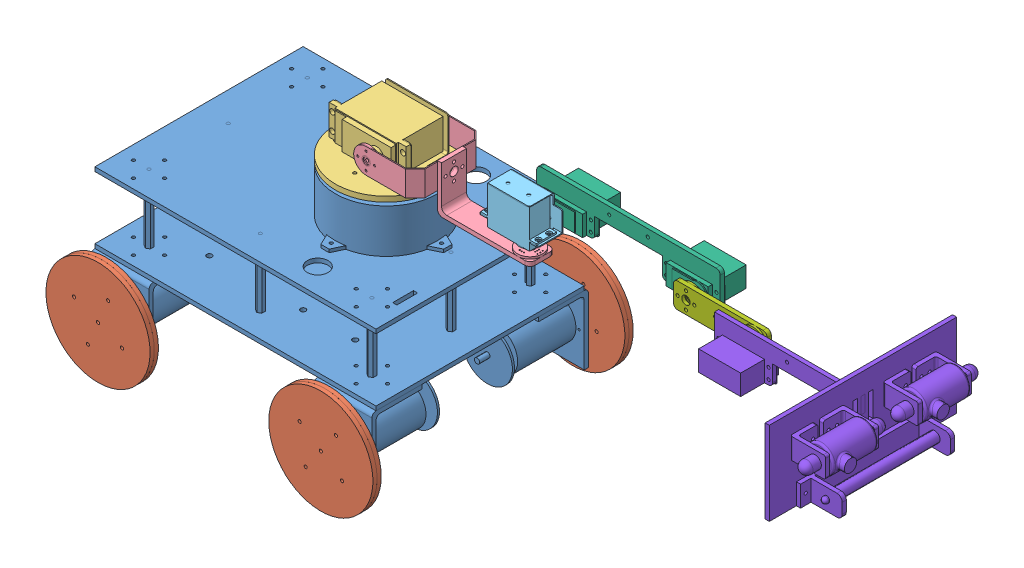
SolidWorks assembly exa_robot16, configuration Default. Lengths in mm.
Overall size (729.39 347.05 342.18).
11 component instances, 8 part files, 26 mates.
Components (placement in the parent):
- base_robot-1: base_robot [Default] at (14.2374 -23.114 -6.4589) size (270 179.13 234)
- roda_robot_fix-1: roda_robot_fix [Default] at (268.1239 -5.9891 251.6556) x (0.408711 0.912664 0) z (0 0 1) size (100 100 21)
- roda_robot_fix-2: roda_robot_fix [Default] at (-24.7206 118.9318 251.6556) x (-0.199609 -0.979876 0) z (0 0 1) size (100 100 21)
- roda_robot_fix-3: roda_robot_fix [Default] at (-43.3679 96.894 162.7099) x (0.933321 0.359042 0) z (0 0 -1) size (100 100 21)
- roda_robot_fix-4: roda_robot_fix [Default] at (229.5868 134.8934 162.7099) x (0.816348 -0.57756 0) z (0 0 -1) size (100 100 21)
- link1_robot-1: link1_robot [Default] at (14.2374 -23.114 -6.4589) size (98 43 98)
- link2_robot-1: link2_robot [Default] at (157.8184 543.2778 -6.4589) x (-0.766044 -0.642788 0) z (0 0 1) size (99.47 123.93 66)
- link3_robot-1: link3_robot [Default] at (157.8184 543.2778 -6.4589) x (-0.766044 -0.642788 0) z (0 0 1) size (56.44 54.96 29)
- link4_robot-1: link4_robot [Default] at (-3.6112 75.6154 -6.4589) x (0.642788 -0.766044 0) z (0 0 1) size (137.73 155 42.35)
- link5_robot-1: link5_robot [Default] at (605.5051 -228.2842 -6.4589) x (0.766044 0.642788 0) z (0 0 1) size (81.1 72.97 14)
- link6_eof_robot-1: link6_eof_robot [Default] at (291.8049 -177.1524 -6.4589) size (184.63 80 180)
Mates (geometry in assembly coordinates):
- Coincident1: coincident anti-aligned: plane of base_robot-1 through (258.5015 16.6149 311.1827) normal (0 0 1); plane of roda_robot_fix-1 through (235.6028 60.827 311.1827) normal (0 0 -1)
- Concentric1: concentric aligned: cylinder of base_robot-1 through (235.6028 60.827 324.1827) axis (0 0 -1) radius 2.5; cylinder of roda_robot_fix-1 through (235.6028 60.827 324.1827) axis (0 0 -1) radius 2.5
- Concentric2: concentric aligned: cylinder of base_robot-1 through (235.6028 60.827 90.1827) axis (0 0 1) radius 2.5; cylinder of roda_robot_fix-4 through (235.6028 60.827 90.1827) axis (0 0 1) radius 2.5
- Coincident3: coincident anti-aligned: plane of base_robot-1 through (212.704 16.6149 103.1827) normal (0 0 -1); plane of roda_robot_fix-4 through (235.6028 60.827 103.1827) normal (0 0 1)
- Coincident4: coincident anti-aligned: plane of base_robot-1 through (-1.296 105.0391 311.1827) normal (0 0 1); plane of roda_robot_fix-2 through (21.6028 60.827 311.1827) normal (0 0 -1)
- Concentric3: concentric aligned: cylinder of base_robot-1 through (21.6028 60.827 324.1827) axis (0 0 -1) radius 2.5; cylinder of roda_robot_fix-2 through (21.6028 60.827 324.1827) axis (0 0 -1) radius 2.5
- Coincident5: coincident anti-aligned: plane of base_robot-1 through (-1.296 16.6149 103.1827) normal (0 0 -1); plane of roda_robot_fix-3 through (21.6028 60.827 103.1827) normal (0 0 1)
- Concentric4: concentric aligned: cylinder of base_robot-1 through (21.6028 60.827 90.1827) axis (0 0 1) radius 2.5; cylinder of roda_robot_fix-3 through (21.6028 60.827 90.1827) axis (0 0 1) radius 2.5
- Coincident6: coincident anti-aligned: plane of base_robot-1 through (183.8898 208.9523 217.0887) normal (0 1 0); plane of link1_robot-1 through (173.6028 208.9523 207.1827) normal (0 -1 0)
- Concentric5: concentric aligned: cylinder of base_robot-1 through (173.6028 189.6967 207.1827) axis (0 1 0) radius 2.8131; cylinder of link1_robot-1 through (173.6028 204.9523 207.1827) axis (0 1 0) radius 3
- Coincident7: coincident anti-aligned: plane of link1_robot-1 through (189.1028 233.9523 239.1727) normal (0 0 1); plane of link2_robot-1 through (189.1028 233.9523 239.1727) normal (0 0 -1)
- Concentric6: concentric anti-aligned: cylinder of link1_robot-1 through (189.1028 233.9523 239.1727) axis (0 0 -1) radius 3; cylinder of link2_robot-1 through (189.1028 233.9523 236.1727) axis (0 0 1) radius 3
- Concentric7: concentric anti-aligned: cylinder of link2_robot-1 through (313.1028 210.9523 208.7585) axis (0 -1 0) radius 3; cylinder of link3_robot-1 through (313.1028 207.9523 208.7585) axis (0 1 0) radius 2.9972
- Coincident9: coincident anti-aligned: plane of link2_robot-1 through (313.1028 207.9523 208.7585) normal (0 1 0); plane of link3_robot-1 through (313.1028 207.9523 208.7585) normal (0 -1 0)
- Coincident10: coincident anti-aligned: plane of link3_robot-1 through (310.9348 228.7318 192.7915) normal (0 0 -1); plane of link4_robot-1 through (310.9348 228.7318 192.7915) normal (0 0 1)
- Concentric8: concentric anti-aligned: cylinder of link3_robot-1 through (310.9348 228.7318 189.7915) axis (0 0 1) radius 3; cylinder of link4_robot-1 through (310.9348 228.7318 192.7915) axis (0 0 -1) radius 2.9972
- Coincident11: coincident anti-aligned: plane of link4_robot-1 through (452.8968 228.2238 192.7915) normal (0 0 1); plane of link5_robot-1 through (452.8968 228.2238 192.7915) normal (0 0 -1)
- Concentric9: concentric anti-aligned: cylinder of link4_robot-1 through (452.8968 228.2238 192.7915) axis (0 0 -1) radius 2.9972; cylinder of link5_robot-1 through (452.8968 228.2238 189.7915) axis (0 0 1) radius 3
- Coincident12: coincident anti-aligned: plane of link5_robot-1 through (518.8968 228.2238 200.7915) normal (0 0 1); plane of link6_eof_robot-1 through (518.8968 228.2238 200.7915) normal (0 0 -1)
- Concentric10: concentric anti-aligned: cylinder of link5_robot-1 through (518.8968 228.2238 203.7915) axis (0 0 -1) radius 3; cylinder of link6_eof_robot-1 through (518.8968 228.2238 200.7915) axis (0 0 1) radius 2.9972
- LimitAngle1: limit planar angle = 0 rad anti-aligned: plane of link1_robot-1 through (173.6028 213.9523 207.1827) normal (0 1 0); plane of link2_robot-1 through (228.0844 221.9523 195.8793) normal (0 -1 0)
- LimitAngle2: limit planar angle = 1.570796 rad anti-aligned: plane of link3_robot-1 through (322.6278 223.3828 218.7915) normal (1 0 0); plane of link2_robot-1 through (286.3647 241.9 220.7585) normal (0 0 1)
- LimitAngle3: limit planar angle = 3.141593 rad aligned: plane of link4_robot-1 through (301.4098 218.6988 177.361) normal (-1 0 0); plane of link3_robot-1 through (322.6278 223.3828 218.7915) normal (1 0 0)
- LimitAngle4: limit planar angle = 1.570796 rad aligned: plane of link4_robot-1 through (462.4218 238.2568 177.361) normal (1 0 0); plane of link5_robot-1 through (440.8968 240.2238 198.7915) normal (0 1 0)
- LimitAngle5: limit planar angle = 1.570796 rad anti-aligned: plane of link5_robot-1 through (440.8968 216.2238 198.7915) normal (0 -1 0); plane of link6_eof_robot-1 through (501.7518 221.3333 216.222) normal (-1 0 0)
- LimitAngle9: limit planar angle = 1.570796 rad anti-aligned: plane of link1_robot-1 through (203.1028 247.9523 225.1827) normal (1 0 0); plane of base_robot-1 through (200.3661 159.827 307.1827) normal (0 0 1)
